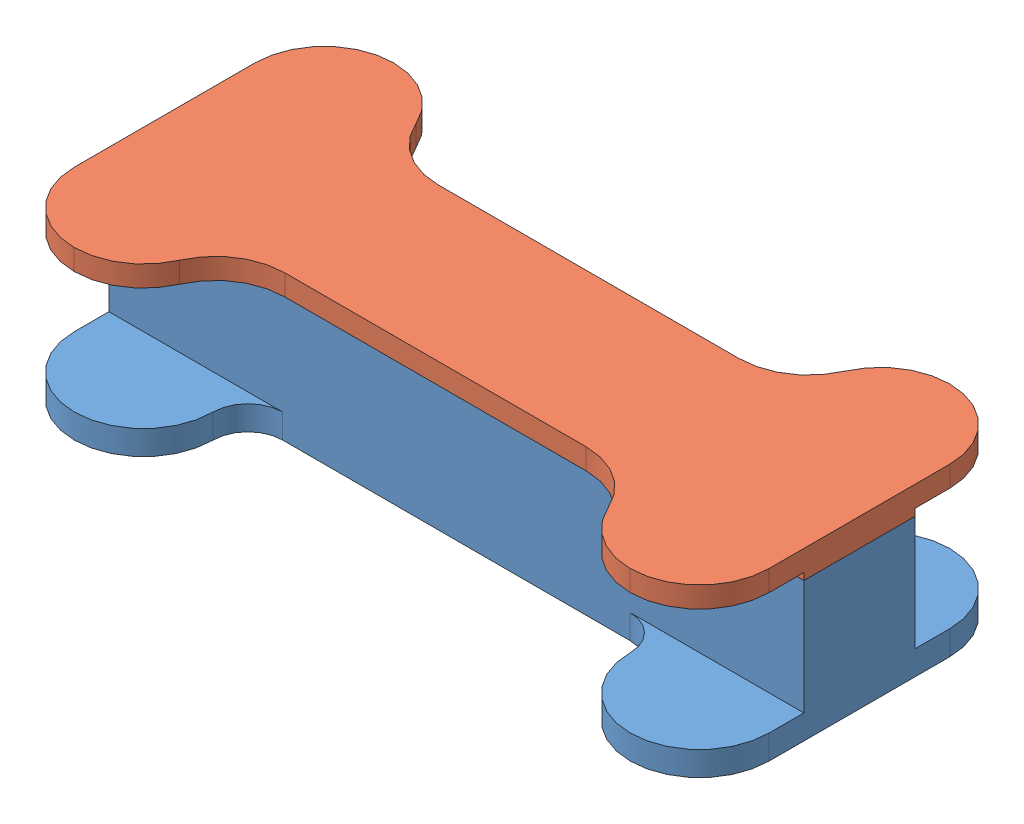
SolidWorks assembly Mold_oct31, configuration Default. Lengths in mm.
Overall size (100 25 46).
2 component instances, 2 part files, 3 mates.
Components (placement in the parent):
- SR_Oct31_female-1: SR_Oct31_female [Default] at (174.9469 -8.4387 128.9121) size (100 22 46)
- SR_oct31_Male-2: SR_oct31_Male [Default] at (-100.1119 15.5613 17.3827) x (1 0 0) z (0 0 -1) size (100 18 46)
Mates (geometry in assembly coordinates):
- Coincident7: coincident: plane of SR_Oct31_female-1 through (-0.1119 11.5613 17.3827) normal (1 0 0); plane of SR_oct31_Male-2 through (-0.1119 27.0325 17.3827) normal (1 0 0)
- Coincident9: coincident: plane of SR_Oct31_female-1 through (-100.1119 11.5613 33.3827) normal (0 0 1); plane of SR_oct31_Male-2 through (-100.1119 24.0325 33.3827) normal (0 0 1)
- Coincident10: coincident: line of SR_Oct31_female-1 through (-99.1619 11.5613 32.4327) axis (1 0 0); plane of SR_oct31_Male-2 through (-100.1119 11.5613 17.3827) normal (0 -1 0)
